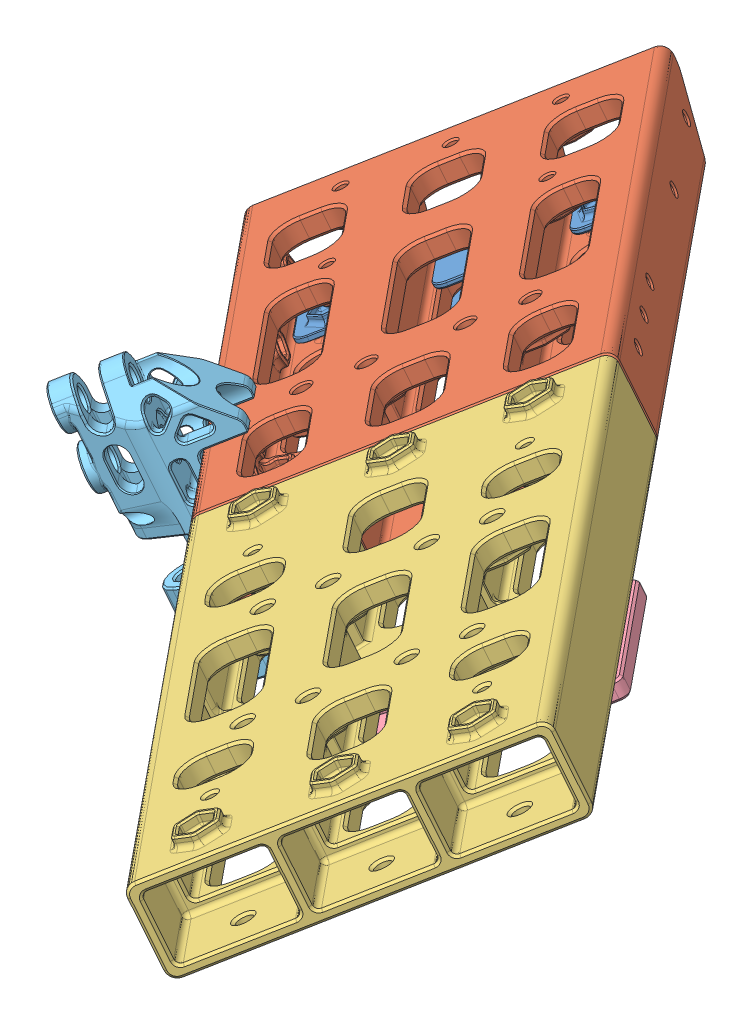
SolidWorks assembly Assem1, configuration Default. Lengths in mm.
Overall size (309.39 155.34 341.94).
5 component instances, 5 part files, 11 mates.
Components (placement in the parent):
- AARL_QR_FR_BO_013.1-1: AARL_QR_FR_BO_013.1 [Default] at (-36.9544 -34.3295 -62.6156) x (0.629951 0.42701 -0.648709) z (-0.641747 -0.184231 -0.744459) size (85.85 17.21 50.16)
- AARL_QR_FR_BO_020 2.1-1: AARL_QR_FR_BO_020 2.1 [Default] at (2.1715 -19.2616 -14.6047) x (0.641747 0.184231 0.744459) z (-0.629951 -0.42701 0.648709) size (190.5 25.4 104.78)
- AARL_QR_FR_BO_001-1: AARL_QR_FR_BO_001 [Default] at (118.3117 14.0795 120.1238) x (0.641747 0.184231 0.744459) z (0.629951 0.42701 -0.648709) size (196.85 28.57 104.77)
- AARL_QR_FR_BO_012.3-1: AARL_QR_FR_BO_012.3 [Default] at (123.7552 0.2369 116.2981) x (-0.629951 -0.42701 0.648709) z (-0.641747 -0.184231 -0.744459) size (104.77 12.7 67.31)
- AARL_QR_FR_BO_007-1: AARL_QR_FR_BO_007 [Default] at (-13.4174 -23.7951 48.0295) x (0.641747 0.184231 0.744459) z (-0.629951 -0.42701 0.648709) size (23.81 79.38 39.69)
Mates (geometry in assembly coordinates):
- Concentric1: concentric aligned: cylinder of AARL_QR_FR_BO_013.1-1 through (-2.3434 -14.5978 -67.3098) axis (0.437404 -0.88528 -0.157976) radius 1.651; cylinder of AARL_QR_FR_BO_020 2.1-1 through (-8.871 -1.3864 -64.9522) axis (0.437404 -0.88528 -0.157976) radius 1.5875
- Parallel9: parallel anti-aligned: plane of AARL_QR_FR_BO_013.1-1 through (-9.9131 -15.9996 -90.462) normal (0.641747 0.184231 0.744459); plane of AARL_QR_FR_BO_020 2.1-1 through (-33.0239 -42.2042 -63.8844) normal (-0.641747 -0.184231 -0.744459)
- Coincident11: coincident anti-aligned: plane of AARL_QR_FR_BO_013.1-1 through (-6.0246 -23.8698 -91.8664) normal (-0.437404 0.88528 0.157976); plane of AARL_QR_FR_BO_020 2.1-1 through (60.7028 -15.2964 44.8441) normal (0.437404 -0.88528 -0.157976)
- Coincident12: coincident anti-aligned: cylinder of AARL_QR_FR_BO_020 2.1-1 through (80.466 21.1801 35.8401) axis (-0.437404 0.88528 0.157976) radius 2.3813; circle of AARL_QR_FR_BO_001-1
- Coincident13: coincident anti-aligned: plane of AARL_QR_FR_BO_020 2.1-1 through (55.1478 -4.0534 46.8504) normal (0.641747 0.184231 0.744459); plane of AARL_QR_FR_BO_001-1 through (55.1478 -4.0534 46.8504) normal (-0.641747 -0.184231 -0.744459)
- Coincident15: coincident anti-aligned: plane of AARL_QR_FR_BO_020 2.1-1 through (75.6144 -7.8062 64.2549) normal (0.437404 -0.88528 -0.157976); plane of AARL_QR_FR_BO_001-1 through (59.314 -12.4857 45.3457) normal (-0.437404 0.88528 0.157976)
- Coincident16: coincident anti-aligned: plane of AARL_QR_FR_BO_001-1 through (170.7303 16.2899 172.4817) normal (0.437404 -0.88528 -0.157976); plane of AARL_QR_FR_BO_012.3-1 through (138.1229 19.8251 62.3876) normal (-0.437404 0.88528 0.157976)
- Concentric8: concentric aligned: cylinder of AARL_QR_FR_BO_001-1 through (72.3435 0.508 137.5193) axis (0.437404 -0.88528 -0.157976) radius 1.5875; cylinder of AARL_QR_FR_BO_012.3-1 through (82.6396 -20.3307 133.8007) axis (0.437404 -0.88528 -0.157976) radius 1.5875
- Coincident17: coincident aligned: circle of AARL_QR_FR_BO_001-1; cylinder of AARL_QR_FR_BO_012.3-1 through (165.0929 26.0054 102.4347) axis (0.437404 -0.88528 -0.157976) radius 1.5875
- Coincident19: coincident anti-aligned: plane of AARL_QR_FR_BO_020 2.1-1 through (22.1462 -26.4234 80.8346) normal (-0.629951 -0.42701 0.648709); plane of AARL_QR_FR_BO_007-1 through (-5.7766 -21.6016 56.8932) normal (0.629951 0.42701 -0.648709)
- Coincident20: coincident anti-aligned: plane of AARL_QR_FR_BO_020 2.1-1 through (49.5927 7.1897 48.8567) normal (-0.437404 0.88528 0.157976); plane of AARL_QR_FR_BO_007-1 through (-5.7766 -21.6016 56.8932) normal (0.437404 -0.88528 -0.157976)
